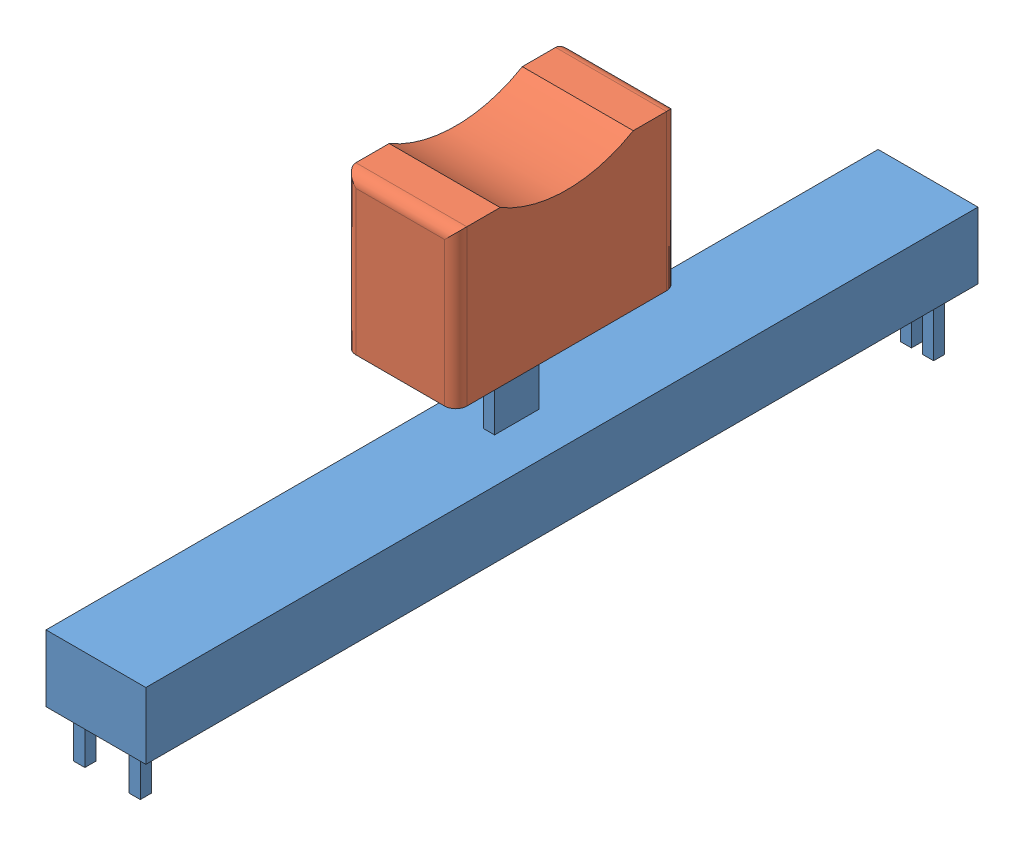
SolidWorks assembly Assempotentiomètre, configuration Default. Lengths in mm.
Overall size (10 35 75).
2 component instances, 2 part files, 3 mates.
Components (placement in the parent):
- potentiometre-1: potentiometre [Default] at (21.4554 37.7055 61.994) size (9 26 75)
- capuchon_potentiomètre-1: capuchon_potentiomètre [Default] at (21.4554 51.7055 62.0657) size (10 16 20)
Mates (geometry in assembly coordinates):
- Coincident1: coincident: plane of potentiometre-1 through (21.9554 58.7055 64.0657) normal (1 0 0); plane of capuchon_potentiomètre-1 through (21.9554 58.7055 64.0657) normal (-1 0 0)
- Coincident2: coincident anti-aligned: plane of potentiometre-1 through (21.4554 58.7055 61.994) normal (0 1 0); plane of capuchon_potentiomètre-1 through (21.4554 58.7055 62.0657) normal (0 -1 0)
- Coincident3: coincident anti-aligned: plane of potentiometre-1 through (20.9554 58.7055 64.0657) normal (0 0 1); plane of capuchon_potentiomètre-1 through (20.9554 58.7055 64.0657) normal (0 0 -1)
